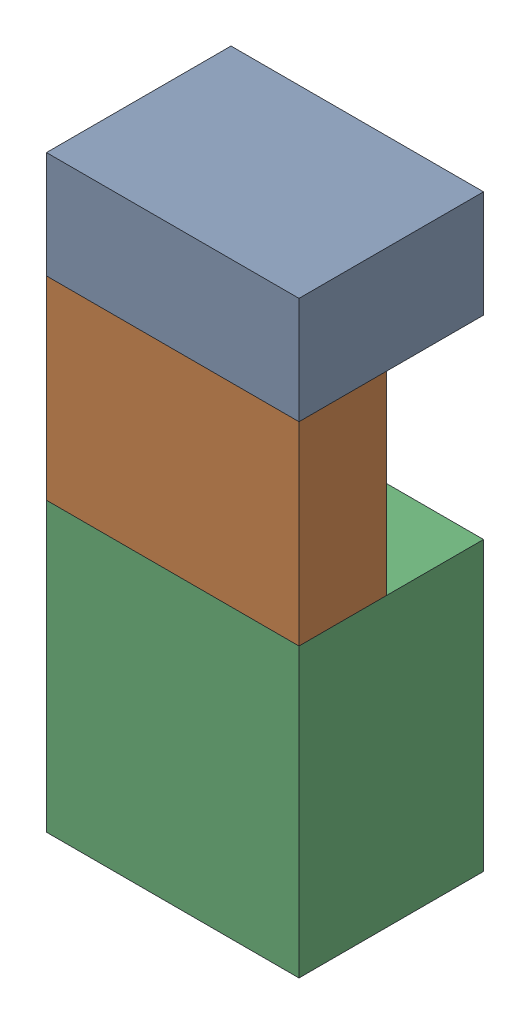
SolidWorks assembly SUP_K11, configuration Default. Lengths in mm.
Overall size (13 30.3 9.5).
6 component instances, 3 part files, 0 mates.
Components (placement in the parent):
- 1151724928-1: 1151724928 [Default] at (159.385 41.975 0) size (13 5.5 9.5)
  - Extruded_2-1: Extruded_2 [Default] at origin size (13 5.5 9.5)
- 1151725064-1: 1151725064 [Default] at (159.385 34.225 5) size (13 10 4.5)
  - Extruded_3-1: Extruded_3 [Default] at origin size (13 10 4.5)
- 1151724792-1: 1151724792 [Default] at (159.385 21.825 0) size (13 14.8 9.5)
  - Extruded_4-1: Extruded_4 [Default] at origin size (13 14.8 9.5)
